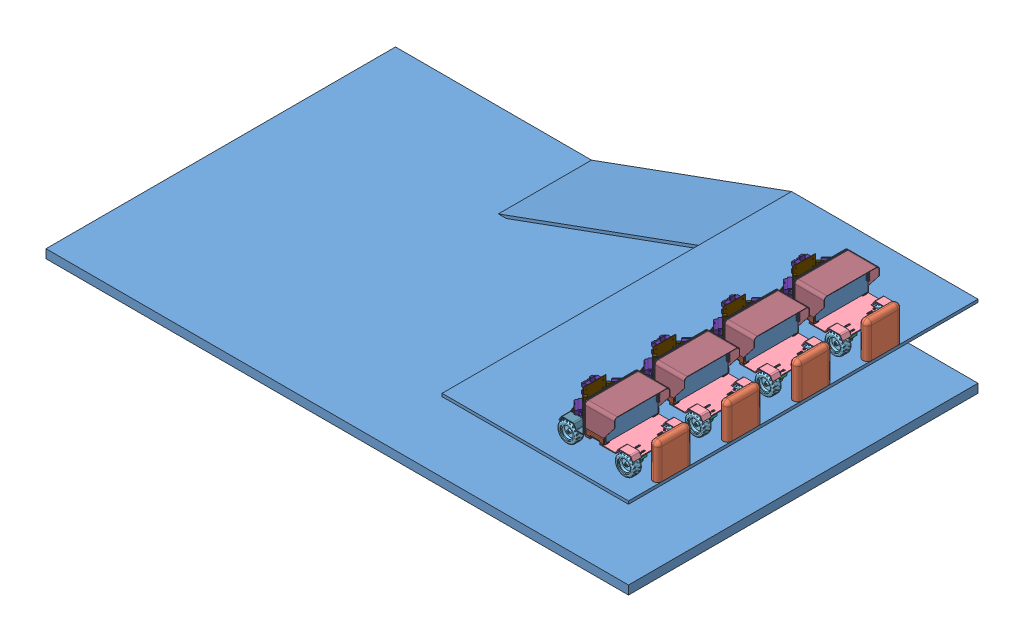
SolidWorks assembly Indoor Testing Course, configuration Default. Lengths in mm.
Overall size (1270 276.79 762).
193 component instances, 20 part files, 15 mates.
Components (placement in the parent):
- Testing Course-1: Testing Course [Default] at (-119.6864 -46.4529 34.3189) size (1270 177.8 762)
- Charging Base-1: Charging Base [Default] at (505.7886 131.3471 313.7189) x (0 0 1) z (-1 0 0) size (76.2 76.2 31.12)
- Charging Base-2: Charging Base [Default] at (505.7886 131.3471 161.3189) x (0 0 1) z (-1 0 0) size (76.2 76.2 31.12)
- Charging Base-3: Charging Base [Default] at (505.7886 131.3471 8.9189) x (0 0 1) z (-1 0 0) size (76.2 76.2 31.12)
- Charging Base-4: Charging Base [Default] at (505.7886 131.3471 -143.4811) x (0 0 1) z (-1 0 0) size (76.2 76.2 31.12)
- Scout Full Assembly-1: Scout Full Assembly [Default] at (379.8221 169.1063 321.6045) x (0 0 1) z (-1 0 0) size (134.41 99.43 167.8)
  - 6655k13 Thrust Washers-1: 6655k13 Thrust Washers [Default] at (-7.8856 2.7539 2.2902) size (14.15 14.15 4.9)
  - Scout Rear End-1: Scout Rear End [Default] at (-50.0168 -32.0545 -46.8811) x (-1 0 0) z (0 0 -1) size (123.38 99.43 114.85)
    - Rear Baseplate-1: Rear Baseplate [Default] at (-42.1312 28.0774 12.7174) size (120.65 65.15 111.6)
    - Pololu Wheel Assembly-1: Pololu Wheel Assembly [Default-_flexible1] at (7.6153 26.9792 58.7651) x (0 0 1) z (1 0 0) size (42.46 78.6 70.03) (flexible)
      - Pololu 49x19 Wheel-1: Pololu 49x19 Wheel [Default] at (-19.8703 11.8393 2.4418) size (42.46 42.56 19)
      - Pololu Extended Micro Metal Bracket-1: Pololu Extended Micro Metal Bracket [Default] at (-19.8703 6.8393 -18.4366) size (26.6 22.49 26.04)
      - Pololu 298-1 Motor-1: Pololu 298-1 Motor [Default] at (-19.8703 11.8393 -25.1366) x (0 0 -1) z (0 1 0) size (35.87 12 10)
    - Pololu Wheel Assembly-2: Pololu Wheel Assembly [Default-_flexible2] at (-91.8778 26.9792 19.0244) x (0 0 -1) z (-1 0 0) size (42.46 78.6 70.03) (flexible)
      - Pololu 49x19 Wheel-1: Pololu 49x19 Wheel [Default] at (-19.8703 11.8393 2.4418) size (42.46 42.56 19)
      - Pololu Extended Micro Metal Bracket-1: Pololu Extended Micro Metal Bracket [Default] at (-19.8703 6.8393 -18.4366) size (26.6 22.49 26.04)
      - Pololu 298-1 Motor-1: Pololu 298-1 Motor [Default] at (-19.8703 11.8393 -25.1366) x (0 0 -1) z (0 1 0) size (35.87 12 10)
    - Socket Head Cap Screw_AI-1: Socket Head Cap Screw_AI [HX-SHCS 0.086-56x0.4375x0.4375-N] at (-77.6912 31.9128 47.8948) x (0 -1 0) z (-0.381305 0 -0.924449) size (13.3 3.56 3.56)
    - Socket Head Cap Screw_AI-2: Socket Head Cap Screw_AI [HX-SHCS 0.086-56x0.4375x0.4375-N] at (-77.6912 31.9128 29.8948) x (0 -1 0) z (0 0 1) size (13.3 3.56 3.56)
    - Socket Head Cap Screw_AI-3: Socket Head Cap Screw_AI [HX-SHCS 0.086-56x0.4375x0.4375-N] at (-6.5712 31.9128 29.8948) x (0 -1 0) z (0 0 1) size (13.3 3.56 3.56)
    - Socket Head Cap Screw_AI-4: Socket Head Cap Screw_AI [HX-SHCS 0.086-56x0.4375x0.4375-N] at (-6.5712 31.9128 47.8948) x (0 -1 0) z (0 0 1) size (13.3 3.56 3.56)
    - 4000mAh 7.4V Battery Pack-1: 4000mAh 7.4V Battery Pack [Default] at (-42.1312 61.2244 -25.7652) x (0 0 -1) z (1 0 0) size (34.29 34.29 68.58)
    - GP2Y0D810 Sensor-1: GP2Y0D810 Sensor [Default] at (9.9271 36.6454 -23.9555) x (0 0 -1) z (0.766044 0.642788 0) size (28.32 10.54 8.89)
    - GP2Y0D810 Sensor-2: GP2Y0D810 Sensor [Default] at (-94.1896 36.6454 -23.9555) x (0 0 -1) z (0.766044 -0.642788 0) size (28.32 10.54 8.89)
    - Battery Support-1: Battery Support [Default] at (-42.1312 29.7284 -26.0192) size (120.65 27.05 38.1)
    - Mounting Block-1: Mounting Block [Default] at (-42.1312 36.0784 -35.6712) x (-1 0 0) z (0 0 -1) size (22.23 12.7 25.4)
    - PCB Cover-1: PCB Cover [Default] at (-42.2227 74.2349 -14.9702) size (120.65 49.28 63.5)
  - Scout Front End-1: Scout Front End [Default] at (-84.349 -50.4844 21.8661) x (-1 0 0) z (0 0 -1) size (134.41 99.37 79.92)
    - Front Baseplate-1: Front Baseplate [Default] at (-76.4634 46.5072 -32.0242) size (120.65 65.15 54.45)
    - Pololu Wheel Assembly-1: Pololu Wheel Assembly [Default-_flexible3] at (-26.7168 45.4091 2.1802) x (0 0 1) z (1 0 0) size (42.46 78.6 70.03) (flexible)
      - Pololu 49x19 Wheel-1: Pololu 49x19 Wheel [Default] at (-19.8703 11.8393 2.4418) size (42.46 42.56 19)
      - Pololu Extended Micro Metal Bracket-1: Pololu Extended Micro Metal Bracket [Default] at (-19.8703 6.8393 -18.4366) size (26.6 22.49 26.04)
      - Pololu 298-1 Motor-1: Pololu 298-1 Motor [Default] at (-19.8703 11.8393 -25.1366) x (0 0 -1) z (0 1 0) size (35.87 12 10)
    - Pololu Wheel Assembly-2: Pololu Wheel Assembly [Default-_flexible4] at (-126.21 45.4091 -37.5605) x (0 0 -1) z (-1 0 0) size (42.46 78.6 70.03) (flexible)
      - Pololu 49x19 Wheel-1: Pololu 49x19 Wheel [Default] at (-19.8703 11.8393 2.4418) size (42.46 42.56 19)
      - Pololu Extended Micro Metal Bracket-1: Pololu Extended Micro Metal Bracket [Default] at (-19.8703 6.8393 -18.4366) size (26.6 22.49 26.04)
      - Pololu 298-1 Motor-1: Pololu 298-1 Motor [Default] at (-19.8703 11.8393 -25.1366) x (0 0 -1) z (0 1 0) size (35.87 12 10)
    - Socket Head Cap Screw_AI-1: Socket Head Cap Screw_AI [HX-SHCS 0.086-56x0.4375x0.4375-N] at (-112.0234 50.3426 -8.6902) x (0 -1 0) z (0.989468 0 0.144748) size (13.3 3.56 3.56)
    - Socket Head Cap Screw_AI-3: Socket Head Cap Screw_AI [HX-SHCS 0.086-56x0.4375x0.4375-N] at (-40.9034 50.3426 -8.6902) x (0 -1 0) z (0.700957 0 0.713204) size (13.3 3.56 3.56)
    - GP2Y0D810 Sensor-2: GP2Y0D810 Sensor [Default] at (-76.7491 52.0249 -21.9932) x (1 0 0) z (0 -0.642788 0.766044) size (28.32 10.54 8.89)
    - Bumper-1: Bumper [Default] at (-76.4634 36.9822 -30.9902) x (-1 0 0) z (0 0 -1) size (69.85 9.53 6.35)
    - Mounting Block-1: Mounting Block [Default] at (-76.4634 54.5082 6.0758) size (22.23 12.7 25.4)
    - Socket Head Shoulder Screw2_AI-1: Socket Head Shoulder Screw2_AI [SHSSCREW 0.25x1.5-N] at (-76.4634 53.2382 -11.3994) x (0 0 1) z (-0.728467 -0.685081 0) size (52.4 9.53 9.53)
    - gp2d12-1: gp2d12 [Default] at (-34.5397 79.9082 -2.2725) x (-0.707107 0 -0.707107) z (0.707107 0 -0.707107) size (44.5 18.9 13.5)
    - gp2d12-2: gp2d12 [Default] at (-76.4634 79.9082 -18.7962) x (-1 0 0) z (0 0 -1) size (44.5 18.9 13.5)
    - gp2d12-3: gp2d12 [Default] at (-118.3871 79.9082 -2.2725) x (-0.707107 0 0.707107) z (-0.707107 0 -0.707107) size (44.5 18.9 13.5)
    - Front IR Mount-1: Front IR Mount [Default] at (-76.4634 73.5582 -18.7962) x (-1 0 0) z (0 0 -1) size (116.89 51.9 52.81)
    - gp2d12-4: gp2d12 [Default] at (-76.4634 93.8782 -18.7962) x (1 0 0) z (0 0 -1) size (44.5 18.9 13.5)
    - Socket Head Cap Screw_AI-5: Socket Head Cap Screw_AI [HX-SHCS 0.086-56x0.4375x0.4375-N] at (-40.9034 51.2773 -26.6902) x (0 -1 0) z (-0.957829 0 -0.287339) size (13.3 3.56 3.56)
    - Socket Head Cap Screw_AI-6: Socket Head Cap Screw_AI [HX-SHCS 0.086-56x0.4375x0.4375-N] at (-112.0234 51.2773 -26.6902) x (0 -1 0) z (-0.957829 0 -0.287339) size (13.3 3.56 3.56)
  - Sensor PCB-1: Sensor PCB [Default] at (-7.8856 37.8059 39.1435) x (-1 0 0) z (0 0 -1) size (111.89 1.6 32.13) (hidden)
  - Main PCB-1: Main PCB [Default] at (-7.8909 30.486 -39.9119) x (1 0 0) z (0 1 0) size (114.3 6.68 57.15)
- Scout Full Assembly-2: Scout Full Assembly [Default] at (379.8221 169.1063 169.2045) x (0 0 1) z (-1 0 0) size (134.41 99.43 167.8)
  - 6655k13 Thrust Washers-1: 6655k13 Thrust Washers [Default] at (-7.8856 2.7539 2.2902) size (14.15 14.15 4.9)
  - Scout Rear End-1: Scout Rear End [Default] at (-50.0168 -32.0545 -46.8811) x (-1 0 0) z (0 0 -1) size (123.38 99.43 114.85)
    - Rear Baseplate-1: Rear Baseplate [Default] at (-42.1312 28.0774 12.7174) size (120.65 65.15 111.6)
    - Pololu Wheel Assembly-1: Pololu Wheel Assembly [Default-_flexible1] at (7.6153 26.9792 58.7651) x (0 0 1) z (1 0 0) size (42.46 78.6 70.03) (flexible)
      - Pololu 49x19 Wheel-1: Pololu 49x19 Wheel [Default] at (-19.8703 11.8393 2.4418) size (42.46 42.56 19)
      - Pololu Extended Micro Metal Bracket-1: Pololu Extended Micro Metal Bracket [Default] at (-19.8703 6.8393 -18.4366) size (26.6 22.49 26.04)
      - Pololu 298-1 Motor-1: Pololu 298-1 Motor [Default] at (-19.8703 11.8393 -25.1366) x (0 0 -1) z (0 1 0) size (35.87 12 10)
    - Pololu Wheel Assembly-2: Pololu Wheel Assembly [Default-_flexible2] at (-91.8778 26.9792 19.0244) x (0 0 -1) z (-1 0 0) size (42.46 78.6 70.03) (flexible)
      - Pololu 49x19 Wheel-1: Pololu 49x19 Wheel [Default] at (-19.8703 11.8393 2.4418) size (42.46 42.56 19)
      - Pololu Extended Micro Metal Bracket-1: Pololu Extended Micro Metal Bracket [Default] at (-19.8703 6.8393 -18.4366) size (26.6 22.49 26.04)
      - Pololu 298-1 Motor-1: Pololu 298-1 Motor [Default] at (-19.8703 11.8393 -25.1366) x (0 0 -1) z (0 1 0) size (35.87 12 10)
    - Socket Head Cap Screw_AI-1: Socket Head Cap Screw_AI [HX-SHCS 0.086-56x0.4375x0.4375-N] at (-77.6912 31.9128 47.8948) x (0 -1 0) z (-0.381305 0 -0.924449) size (13.3 3.56 3.56)
    - Socket Head Cap Screw_AI-2: Socket Head Cap Screw_AI [HX-SHCS 0.086-56x0.4375x0.4375-N] at (-77.6912 31.9128 29.8948) x (0 -1 0) z (0 0 1) size (13.3 3.56 3.56)
    - Socket Head Cap Screw_AI-3: Socket Head Cap Screw_AI [HX-SHCS 0.086-56x0.4375x0.4375-N] at (-6.5712 31.9128 29.8948) x (0 -1 0) z (0 0 1) size (13.3 3.56 3.56)
    - Socket Head Cap Screw_AI-4: Socket Head Cap Screw_AI [HX-SHCS 0.086-56x0.4375x0.4375-N] at (-6.5712 31.9128 47.8948) x (0 -1 0) z (0 0 1) size (13.3 3.56 3.56)
    - 4000mAh 7.4V Battery Pack-1: 4000mAh 7.4V Battery Pack [Default] at (-42.1312 61.2244 -25.7652) x (0 0 -1) z (1 0 0) size (34.29 34.29 68.58)
    - GP2Y0D810 Sensor-1: GP2Y0D810 Sensor [Default] at (9.9271 36.6454 -23.9555) x (0 0 -1) z (0.766044 0.642788 0) size (28.32 10.54 8.89)
    - GP2Y0D810 Sensor-2: GP2Y0D810 Sensor [Default] at (-94.1896 36.6454 -23.9555) x (0 0 -1) z (0.766044 -0.642788 0) size (28.32 10.54 8.89)
    - Battery Support-1: Battery Support [Default] at (-42.1312 29.7284 -26.0192) size (120.65 27.05 38.1)
    - Mounting Block-1: Mounting Block [Default] at (-42.1312 36.0784 -35.6712) x (-1 0 0) z (0 0 -1) size (22.23 12.7 25.4)
    - PCB Cover-1: PCB Cover [Default] at (-42.2227 74.2349 -14.9702) size (120.65 49.28 63.5)
  - Scout Front End-1: Scout Front End [Default] at (-84.349 -50.4844 21.8661) x (-1 0 0) z (0 0 -1) size (134.41 99.37 79.92)
    - Front Baseplate-1: Front Baseplate [Default] at (-76.4634 46.5072 -32.0242) size (120.65 65.15 54.45)
    - Pololu Wheel Assembly-1: Pololu Wheel Assembly [Default-_flexible3] at (-26.7168 45.4091 2.1802) x (0 0 1) z (1 0 0) size (42.46 78.6 70.03) (flexible)
      - Pololu 49x19 Wheel-1: Pololu 49x19 Wheel [Default] at (-19.8703 11.8393 2.4418) size (42.46 42.56 19)
      - Pololu Extended Micro Metal Bracket-1: Pololu Extended Micro Metal Bracket [Default] at (-19.8703 6.8393 -18.4366) size (26.6 22.49 26.04)
      - Pololu 298-1 Motor-1: Pololu 298-1 Motor [Default] at (-19.8703 11.8393 -25.1366) x (0 0 -1) z (0 1 0) size (35.87 12 10)
    - Pololu Wheel Assembly-2: Pololu Wheel Assembly [Default-_flexible4] at (-126.21 45.4091 -37.5605) x (0 0 -1) z (-1 0 0) size (42.46 78.6 70.03) (flexible)
      - Pololu 49x19 Wheel-1: Pololu 49x19 Wheel [Default] at (-19.8703 11.8393 2.4418) size (42.46 42.56 19)
      - Pololu Extended Micro Metal Bracket-1: Pololu Extended Micro Metal Bracket [Default] at (-19.8703 6.8393 -18.4366) size (26.6 22.49 26.04)
      - Pololu 298-1 Motor-1: Pololu 298-1 Motor [Default] at (-19.8703 11.8393 -25.1366) x (0 0 -1) z (0 1 0) size (35.87 12 10)
    - Socket Head Cap Screw_AI-1: Socket Head Cap Screw_AI [HX-SHCS 0.086-56x0.4375x0.4375-N] at (-112.0234 50.3426 -8.6902) x (0 -1 0) z (0.989468 0 0.144748) size (13.3 3.56 3.56)
    - Socket Head Cap Screw_AI-3: Socket Head Cap Screw_AI [HX-SHCS 0.086-56x0.4375x0.4375-N] at (-40.9034 50.3426 -8.6902) x (0 -1 0) z (0.700957 0 0.713204) size (13.3 3.56 3.56)
    - GP2Y0D810 Sensor-2: GP2Y0D810 Sensor [Default] at (-76.7491 52.0249 -21.9932) x (1 0 0) z (0 -0.642788 0.766044) size (28.32 10.54 8.89)
    - Bumper-1: Bumper [Default] at (-76.4634 36.9822 -30.9902) x (-1 0 0) z (0 0 -1) size (69.85 9.53 6.35)
    - Mounting Block-1: Mounting Block [Default] at (-76.4634 54.5082 6.0758) size (22.23 12.7 25.4)
    - Socket Head Shoulder Screw2_AI-1: Socket Head Shoulder Screw2_AI [SHSSCREW 0.25x1.5-N] at (-76.4634 53.2382 -11.3994) x (0 0 1) z (-0.728467 -0.685081 0) size (52.4 9.53 9.53)
    - gp2d12-1: gp2d12 [Default] at (-34.5397 79.9082 -2.2725) x (-0.707107 0 -0.707107) z (0.707107 0 -0.707107) size (44.5 18.9 13.5)
    - gp2d12-2: gp2d12 [Default] at (-76.4634 79.9082 -18.7962) x (-1 0 0) z (0 0 -1) size (44.5 18.9 13.5)
    - gp2d12-3: gp2d12 [Default] at (-118.3871 79.9082 -2.2725) x (-0.707107 0 0.707107) z (-0.707107 0 -0.707107) size (44.5 18.9 13.5)
    - Front IR Mount-1: Front IR Mount [Default] at (-76.4634 73.5582 -18.7962) x (-1 0 0) z (0 0 -1) size (116.89 51.9 52.81)
    - gp2d12-4: gp2d12 [Default] at (-76.4634 93.8782 -18.7962) x (1 0 0) z (0 0 -1) size (44.5 18.9 13.5)
    - Socket Head Cap Screw_AI-5: Socket Head Cap Screw_AI [HX-SHCS 0.086-56x0.4375x0.4375-N] at (-40.9034 51.2773 -26.6902) x (0 -1 0) z (-0.957829 0 -0.287339) size (13.3 3.56 3.56)
    - Socket Head Cap Screw_AI-6: Socket Head Cap Screw_AI [HX-SHCS 0.086-56x0.4375x0.4375-N] at (-112.0234 51.2773 -26.6902) x (0 -1 0) z (-0.957829 0 -0.287339) size (13.3 3.56 3.56)
  - Sensor PCB-1: Sensor PCB [Default] at (-7.8856 37.8059 39.1435) x (-1 0 0) z (0 0 -1) size (111.89 1.6 32.13) (hidden)
  - Main PCB-1: Main PCB [Default] at (-7.8909 30.486 -39.9119) x (1 0 0) z (0 1 0) size (114.3 6.68 57.15)
- Scout Full Assembly-3: Scout Full Assembly [Default] at (379.8221 169.1063 16.8045) x (0 0 1) z (-1 0 0) size (134.41 99.43 167.8)
  - 6655k13 Thrust Washers-1: 6655k13 Thrust Washers [Default] at (-7.8856 2.7539 2.2902) size (14.15 14.15 4.9)
  - Scout Rear End-1: Scout Rear End [Default] at (-50.0168 -32.0545 -46.8811) x (-1 0 0) z (0 0 -1) size (123.38 99.43 114.85)
    - Rear Baseplate-1: Rear Baseplate [Default] at (-42.1312 28.0774 12.7174) size (120.65 65.15 111.6)
    - Pololu Wheel Assembly-1: Pololu Wheel Assembly [Default-_flexible1] at (7.6153 26.9792 58.7651) x (0 0 1) z (1 0 0) size (42.46 78.6 70.03) (flexible)
      - Pololu 49x19 Wheel-1: Pololu 49x19 Wheel [Default] at (-19.8703 11.8393 2.4418) size (42.46 42.56 19)
      - Pololu Extended Micro Metal Bracket-1: Pololu Extended Micro Metal Bracket [Default] at (-19.8703 6.8393 -18.4366) size (26.6 22.49 26.04)
      - Pololu 298-1 Motor-1: Pololu 298-1 Motor [Default] at (-19.8703 11.8393 -25.1366) x (0 0 -1) z (0 1 0) size (35.87 12 10)
    - Pololu Wheel Assembly-2: Pololu Wheel Assembly [Default-_flexible2] at (-91.8778 26.9792 19.0244) x (0 0 -1) z (-1 0 0) size (42.46 78.6 70.03) (flexible)
      - Pololu 49x19 Wheel-1: Pololu 49x19 Wheel [Default] at (-19.8703 11.8393 2.4418) size (42.46 42.56 19)
      - Pololu Extended Micro Metal Bracket-1: Pololu Extended Micro Metal Bracket [Default] at (-19.8703 6.8393 -18.4366) size (26.6 22.49 26.04)
      - Pololu 298-1 Motor-1: Pololu 298-1 Motor [Default] at (-19.8703 11.8393 -25.1366) x (0 0 -1) z (0 1 0) size (35.87 12 10)
    - Socket Head Cap Screw_AI-1: Socket Head Cap Screw_AI [HX-SHCS 0.086-56x0.4375x0.4375-N] at (-77.6912 31.9128 47.8948) x (0 -1 0) z (-0.381305 0 -0.924449) size (13.3 3.56 3.56)
    - Socket Head Cap Screw_AI-2: Socket Head Cap Screw_AI [HX-SHCS 0.086-56x0.4375x0.4375-N] at (-77.6912 31.9128 29.8948) x (0 -1 0) z (0 0 1) size (13.3 3.56 3.56)
    - Socket Head Cap Screw_AI-3: Socket Head Cap Screw_AI [HX-SHCS 0.086-56x0.4375x0.4375-N] at (-6.5712 31.9128 29.8948) x (0 -1 0) z (0 0 1) size (13.3 3.56 3.56)
    - Socket Head Cap Screw_AI-4: Socket Head Cap Screw_AI [HX-SHCS 0.086-56x0.4375x0.4375-N] at (-6.5712 31.9128 47.8948) x (0 -1 0) z (0 0 1) size (13.3 3.56 3.56)
    - 4000mAh 7.4V Battery Pack-1: 4000mAh 7.4V Battery Pack [Default] at (-42.1312 61.2244 -25.7652) x (0 0 -1) z (1 0 0) size (34.29 34.29 68.58)
    - GP2Y0D810 Sensor-1: GP2Y0D810 Sensor [Default] at (9.9271 36.6454 -23.9555) x (0 0 -1) z (0.766044 0.642788 0) size (28.32 10.54 8.89)
    - GP2Y0D810 Sensor-2: GP2Y0D810 Sensor [Default] at (-94.1896 36.6454 -23.9555) x (0 0 -1) z (0.766044 -0.642788 0) size (28.32 10.54 8.89)
    - Battery Support-1: Battery Support [Default] at (-42.1312 29.7284 -26.0192) size (120.65 27.05 38.1)
    - Mounting Block-1: Mounting Block [Default] at (-42.1312 36.0784 -35.6712) x (-1 0 0) z (0 0 -1) size (22.23 12.7 25.4)
    - PCB Cover-1: PCB Cover [Default] at (-42.2227 74.2349 -14.9702) size (120.65 49.28 63.5)
  - Scout Front End-1: Scout Front End [Default] at (-84.349 -50.4844 21.8661) x (-1 0 0) z (0 0 -1) size (134.41 99.37 79.92)
    - Front Baseplate-1: Front Baseplate [Default] at (-76.4634 46.5072 -32.0242) size (120.65 65.15 54.45)
    - Pololu Wheel Assembly-1: Pololu Wheel Assembly [Default-_flexible3] at (-26.7168 45.4091 2.1802) x (0 0 1) z (1 0 0) size (42.46 78.6 70.03) (flexible)
      - Pololu 49x19 Wheel-1: Pololu 49x19 Wheel [Default] at (-19.8703 11.8393 2.4418) size (42.46 42.56 19)
      - Pololu Extended Micro Metal Bracket-1: Pololu Extended Micro Metal Bracket [Default] at (-19.8703 6.8393 -18.4366) size (26.6 22.49 26.04)
      - Pololu 298-1 Motor-1: Pololu 298-1 Motor [Default] at (-19.8703 11.8393 -25.1366) x (0 0 -1) z (0 1 0) size (35.87 12 10)
    - Pololu Wheel Assembly-2: Pololu Wheel Assembly [Default-_flexible4] at (-126.21 45.4091 -37.5605) x (0 0 -1) z (-1 0 0) size (42.46 78.6 70.03) (flexible)
      - Pololu 49x19 Wheel-1: Pololu 49x19 Wheel [Default] at (-19.8703 11.8393 2.4418) size (42.46 42.56 19)
      - Pololu Extended Micro Metal Bracket-1: Pololu Extended Micro Metal Bracket [Default] at (-19.8703 6.8393 -18.4366) size (26.6 22.49 26.04)
      - Pololu 298-1 Motor-1: Pololu 298-1 Motor [Default] at (-19.8703 11.8393 -25.1366) x (0 0 -1) z (0 1 0) size (35.87 12 10)
    - Socket Head Cap Screw_AI-1: Socket Head Cap Screw_AI [HX-SHCS 0.086-56x0.4375x0.4375-N] at (-112.0234 50.3426 -8.6902) x (0 -1 0) z (0.989468 0 0.144748) size (13.3 3.56 3.56)
    - Socket Head Cap Screw_AI-3: Socket Head Cap Screw_AI [HX-SHCS 0.086-56x0.4375x0.4375-N] at (-40.9034 50.3426 -8.6902) x (0 -1 0) z (0.700957 0 0.713204) size (13.3 3.56 3.56)
    - GP2Y0D810 Sensor-2: GP2Y0D810 Sensor [Default] at (-76.7491 52.0249 -21.9932) x (1 0 0) z (0 -0.642788 0.766044) size (28.32 10.54 8.89)
    - Bumper-1: Bumper [Default] at (-76.4634 36.9822 -30.9902) x (-1 0 0) z (0 0 -1) size (69.85 9.53 6.35)
    - Mounting Block-1: Mounting Block [Default] at (-76.4634 54.5082 6.0758) size (22.23 12.7 25.4)
    - Socket Head Shoulder Screw2_AI-1: Socket Head Shoulder Screw2_AI [SHSSCREW 0.25x1.5-N] at (-76.4634 53.2382 -11.3994) x (0 0 1) z (-0.728467 -0.685081 0) size (52.4 9.53 9.53)
    - gp2d12-1: gp2d12 [Default] at (-34.5397 79.9082 -2.2725) x (-0.707107 0 -0.707107) z (0.707107 0 -0.707107) size (44.5 18.9 13.5)
    - gp2d12-2: gp2d12 [Default] at (-76.4634 79.9082 -18.7962) x (-1 0 0) z (0 0 -1) size (44.5 18.9 13.5)
    - gp2d12-3: gp2d12 [Default] at (-118.3871 79.9082 -2.2725) x (-0.707107 0 0.707107) z (-0.707107 0 -0.707107) size (44.5 18.9 13.5)
    - Front IR Mount-1: Front IR Mount [Default] at (-76.4634 73.5582 -18.7962) x (-1 0 0) z (0 0 -1) size (116.89 51.9 52.81)
    - gp2d12-4: gp2d12 [Default] at (-76.4634 93.8782 -18.7962) x (1 0 0) z (0 0 -1) size (44.5 18.9 13.5)
    - Socket Head Cap Screw_AI-5: Socket Head Cap Screw_AI [HX-SHCS 0.086-56x0.4375x0.4375-N] at (-40.9034 51.2773 -26.6902) x (0 -1 0) z (-0.957829 0 -0.287339) size (13.3 3.56 3.56)
    - Socket Head Cap Screw_AI-6: Socket Head Cap Screw_AI [HX-SHCS 0.086-56x0.4375x0.4375-N] at (-112.0234 51.2773 -26.6902) x (0 -1 0) z (-0.957829 0 -0.287339) size (13.3 3.56 3.56)
  - Sensor PCB-1: Sensor PCB [Default] at (-7.8856 37.8059 39.1435) x (-1 0 0) z (0 0 -1) size (111.89 1.6 32.13) (hidden)
  - Main PCB-1: Main PCB [Default] at (-7.8909 30.486 -39.9119) x (1 0 0) z (0 1 0) size (114.3 6.68 57.15)
- Scout Full Assembly-4: Scout Full Assembly [Default] at (379.8221 169.1063 -135.5955) x (0 0 1) z (-1 0 0) size (134.41 99.43 167.8)
  - 6655k13 Thrust Washers-1: 6655k13 Thrust Washers [Default] at (-7.8856 2.7539 2.2902) size (14.15 14.15 4.9)
  - Scout Rear End-1: Scout Rear End [Default] at (-50.0168 -32.0545 -46.8811) x (-1 0 0) z (0 0 -1) size (123.38 99.43 114.85)
    - Rear Baseplate-1: Rear Baseplate [Default] at (-42.1312 28.0774 12.7174) size (120.65 65.15 111.6)
    - Pololu Wheel Assembly-1: Pololu Wheel Assembly [Default-_flexible1] at (7.6153 26.9792 58.7651) x (0 0 1) z (1 0 0) size (42.46 78.6 70.03) (flexible)
      - Pololu 49x19 Wheel-1: Pololu 49x19 Wheel [Default] at (-19.8703 11.8393 2.4418) size (42.46 42.56 19)
      - Pololu Extended Micro Metal Bracket-1: Pololu Extended Micro Metal Bracket [Default] at (-19.8703 6.8393 -18.4366) size (26.6 22.49 26.04)
      - Pololu 298-1 Motor-1: Pololu 298-1 Motor [Default] at (-19.8703 11.8393 -25.1366) x (0 0 -1) z (0 1 0) size (35.87 12 10)
    - Pololu Wheel Assembly-2: Pololu Wheel Assembly [Default-_flexible2] at (-91.8778 26.9792 19.0244) x (0 0 -1) z (-1 0 0) size (42.46 78.6 70.03) (flexible)
      - Pololu 49x19 Wheel-1: Pololu 49x19 Wheel [Default] at (-19.8703 11.8393 2.4418) size (42.46 42.56 19)
      - Pololu Extended Micro Metal Bracket-1: Pololu Extended Micro Metal Bracket [Default] at (-19.8703 6.8393 -18.4366) size (26.6 22.49 26.04)
      - Pololu 298-1 Motor-1: Pololu 298-1 Motor [Default] at (-19.8703 11.8393 -25.1366) x (0 0 -1) z (0 1 0) size (35.87 12 10)
    - Socket Head Cap Screw_AI-1: Socket Head Cap Screw_AI [HX-SHCS 0.086-56x0.4375x0.4375-N] at (-77.6912 31.9128 47.8948) x (0 -1 0) z (-0.381305 0 -0.924449) size (13.3 3.56 3.56)
    - Socket Head Cap Screw_AI-2: Socket Head Cap Screw_AI [HX-SHCS 0.086-56x0.4375x0.4375-N] at (-77.6912 31.9128 29.8948) x (0 -1 0) z (0 0 1) size (13.3 3.56 3.56)
    - Socket Head Cap Screw_AI-3: Socket Head Cap Screw_AI [HX-SHCS 0.086-56x0.4375x0.4375-N] at (-6.5712 31.9128 29.8948) x (0 -1 0) z (0 0 1) size (13.3 3.56 3.56)
    - Socket Head Cap Screw_AI-4: Socket Head Cap Screw_AI [HX-SHCS 0.086-56x0.4375x0.4375-N] at (-6.5712 31.9128 47.8948) x (0 -1 0) z (0 0 1) size (13.3 3.56 3.56)
    - 4000mAh 7.4V Battery Pack-1: 4000mAh 7.4V Battery Pack [Default] at (-42.1312 61.2244 -25.7652) x (0 0 -1) z (1 0 0) size (34.29 34.29 68.58)
    - GP2Y0D810 Sensor-1: GP2Y0D810 Sensor [Default] at (9.9271 36.6454 -23.9555) x (0 0 -1) z (0.766044 0.642788 0) size (28.32 10.54 8.89)
    - GP2Y0D810 Sensor-2: GP2Y0D810 Sensor [Default] at (-94.1896 36.6454 -23.9555) x (0 0 -1) z (0.766044 -0.642788 0) size (28.32 10.54 8.89)
    - Battery Support-1: Battery Support [Default] at (-42.1312 29.7284 -26.0192) size (120.65 27.05 38.1)
    - Mounting Block-1: Mounting Block [Default] at (-42.1312 36.0784 -35.6712) x (-1 0 0) z (0 0 -1) size (22.23 12.7 25.4)
    - PCB Cover-1: PCB Cover [Default] at (-42.2227 74.2349 -14.9702) size (120.65 49.28 63.5)
  - Scout Front End-1: Scout Front End [Default] at (-84.349 -50.4844 21.8661) x (-1 0 0) z (0 0 -1) size (134.41 99.37 79.92)
    - Front Baseplate-1: Front Baseplate [Default] at (-76.4634 46.5072 -32.0242) size (120.65 65.15 54.45)
    - Pololu Wheel Assembly-1: Pololu Wheel Assembly [Default-_flexible3] at (-26.7168 45.4091 2.1802) x (0 0 1) z (1 0 0) size (42.46 78.6 70.03) (flexible)
      - Pololu 49x19 Wheel-1: Pololu 49x19 Wheel [Default] at (-19.8703 11.8393 2.4418) size (42.46 42.56 19)
      - Pololu Extended Micro Metal Bracket-1: Pololu Extended Micro Metal Bracket [Default] at (-19.8703 6.8393 -18.4366) size (26.6 22.49 26.04)
      - Pololu 298-1 Motor-1: Pololu 298-1 Motor [Default] at (-19.8703 11.8393 -25.1366) x (0 0 -1) z (0 1 0) size (35.87 12 10)
    - Pololu Wheel Assembly-2: Pololu Wheel Assembly [Default-_flexible4] at (-126.21 45.4091 -37.5605) x (0 0 -1) z (-1 0 0) size (42.46 78.6 70.03) (flexible)
      - Pololu 49x19 Wheel-1: Pololu 49x19 Wheel [Default] at (-19.8703 11.8393 2.4418) size (42.46 42.56 19)
      - Pololu Extended Micro Metal Bracket-1: Pololu Extended Micro Metal Bracket [Default] at (-19.8703 6.8393 -18.4366) size (26.6 22.49 26.04)
      - Pololu 298-1 Motor-1: Pololu 298-1 Motor [Default] at (-19.8703 11.8393 -25.1366) x (0 0 -1) z (0 1 0) size (35.87 12 10)
    - Socket Head Cap Screw_AI-1: Socket Head Cap Screw_AI [HX-SHCS 0.086-56x0.4375x0.4375-N] at (-112.0234 50.3426 -8.6902) x (0 -1 0) z (0.989468 0 0.144748) size (13.3 3.56 3.56)
    - Socket Head Cap Screw_AI-3: Socket Head Cap Screw_AI [HX-SHCS 0.086-56x0.4375x0.4375-N] at (-40.9034 50.3426 -8.6902) x (0 -1 0) z (0.700957 0 0.713204) size (13.3 3.56 3.56)
    - GP2Y0D810 Sensor-2: GP2Y0D810 Sensor [Default] at (-76.7491 52.0249 -21.9932) x (1 0 0) z (0 -0.642788 0.766044) size (28.32 10.54 8.89)
    - Bumper-1: Bumper [Default] at (-76.4634 36.9822 -30.9902) x (-1 0 0) z (0 0 -1) size (69.85 9.53 6.35)
    - Mounting Block-1: Mounting Block [Default] at (-76.4634 54.5082 6.0758) size (22.23 12.7 25.4)
    - Socket Head Shoulder Screw2_AI-1: Socket Head Shoulder Screw2_AI [SHSSCREW 0.25x1.5-N] at (-76.4634 53.2382 -11.3994) x (0 0 1) z (-0.728467 -0.685081 0) size (52.4 9.53 9.53)
    - gp2d12-1: gp2d12 [Default] at (-34.5397 79.9082 -2.2725) x (-0.707107 0 -0.707107) z (0.707107 0 -0.707107) size (44.5 18.9 13.5)
    - gp2d12-2: gp2d12 [Default] at (-76.4634 79.9082 -18.7962) x (-1 0 0) z (0 0 -1) size (44.5 18.9 13.5)
    - gp2d12-3: gp2d12 [Default] at (-118.3871 79.9082 -2.2725) x (-0.707107 0 0.707107) z (-0.707107 0 -0.707107) size (44.5 18.9 13.5)
    - Front IR Mount-1: Front IR Mount [Default] at (-76.4634 73.5582 -18.7962) x (-1 0 0) z (0 0 -1) size (116.89 51.9 52.81)
    - gp2d12-4: gp2d12 [Default] at (-76.4634 93.8782 -18.7962) x (1 0 0) z (0 0 -1) size (44.5 18.9 13.5)
    - Socket Head Cap Screw_AI-5: Socket Head Cap Screw_AI [HX-SHCS 0.086-56x0.4375x0.4375-N] at (-40.9034 51.2773 -26.6902) x (0 -1 0) z (-0.957829 0 -0.287339) size (13.3 3.56 3.56)
    - Socket Head Cap Screw_AI-6: Socket Head Cap Screw_AI [HX-SHCS 0.086-56x0.4375x0.4375-N] at (-112.0234 51.2773 -26.6902) x (0 -1 0) z (-0.957829 0 -0.287339) size (13.3 3.56 3.56)
  - Sensor PCB-1: Sensor PCB [Default] at (-7.8856 37.8059 39.1435) x (-1 0 0) z (0 0 -1) size (111.89 1.6 32.13) (hidden)
  - Main PCB-1: Main PCB [Default] at (-7.8909 30.486 -39.9119) x (1 0 0) z (0 1 0) size (114.3 6.68 57.15)
Mates (geometry in assembly coordinates):
- Coincident1: coincident aligned: plane of Charging Base-3 through (515.3136 131.3471 47.0189) normal (0 -1 0); plane of Charging Base-4 through (515.3136 131.3471 -105.3811) normal (0 -1 0)
- Coincident2: coincident aligned: plane of Charging Base-2 through (515.3136 131.3471 199.4189) normal (0 -1 0); plane of Charging Base-3 through (515.3136 131.3471 47.0189) normal (0 -1 0)
- Coincident3: coincident aligned: plane of Charging Base-1 through (515.3136 131.3471 351.8189) normal (0 -1 0); plane of Charging Base-2 through (515.3136 131.3471 199.4189) normal (0 -1 0)
- Coincident4: coincident anti-aligned: plane of Testing Course-1 through (515.3136 131.3471 -346.6811) normal (0 1 0); plane of Charging Base-1 through (515.3136 131.3471 351.8189) normal (0 -1 0)
- Coincident5: coincident aligned: plane of Charging Base-1 through (515.3136 207.5471 275.6189) normal (1 0 0); plane of Charging Base-2 through (515.3136 207.5471 123.2189) normal (1 0 0)
- Coincident6: coincident aligned: plane of Charging Base-2 through (515.3136 207.5471 123.2189) normal (1 0 0); plane of Charging Base-3 through (515.3136 207.5471 -29.1811) normal (1 0 0)
- Coincident7: coincident aligned: plane of Charging Base-3 through (515.3136 207.5471 -29.1811) normal (1 0 0); plane of Charging Base-4 through (515.3136 207.5471 -181.5811) normal (1 0 0)
- Coincident8: coincident aligned: plane of Charging Base-1 through (515.3136 207.5471 275.6189) normal (1 0 0); plane of Testing Course-1 through (515.3136 131.3471 415.3189) normal (1 0 0)
- Coincident9: coincident aligned: unknown of Charging Base-1
- Coincident10: coincident aligned: unknown of Charging Base-2
- Coincident11: coincident aligned: unknown of Charging Base-3
- Coincident12: coincident aligned: unknown of Charging Base-4
- Distance1: distance = 33.782 mm anti-aligned: plane of Testing Course-1 through (515.3136 131.3471 -346.6811) normal (0 1 0); plane of Scout Full Assembly-1/Scout Rear End-1/Rear Baseplate-1 through (445.642 165.1291 353.7239) normal (0 -1 0)
- Coincident14: coincident anti-aligned: unknown of Scout Full Assembly-1/Scout Rear End-1/Rear Baseplate-1
- PLANE1: unknown = 101.6 mm: unknown of Testing Course-1
